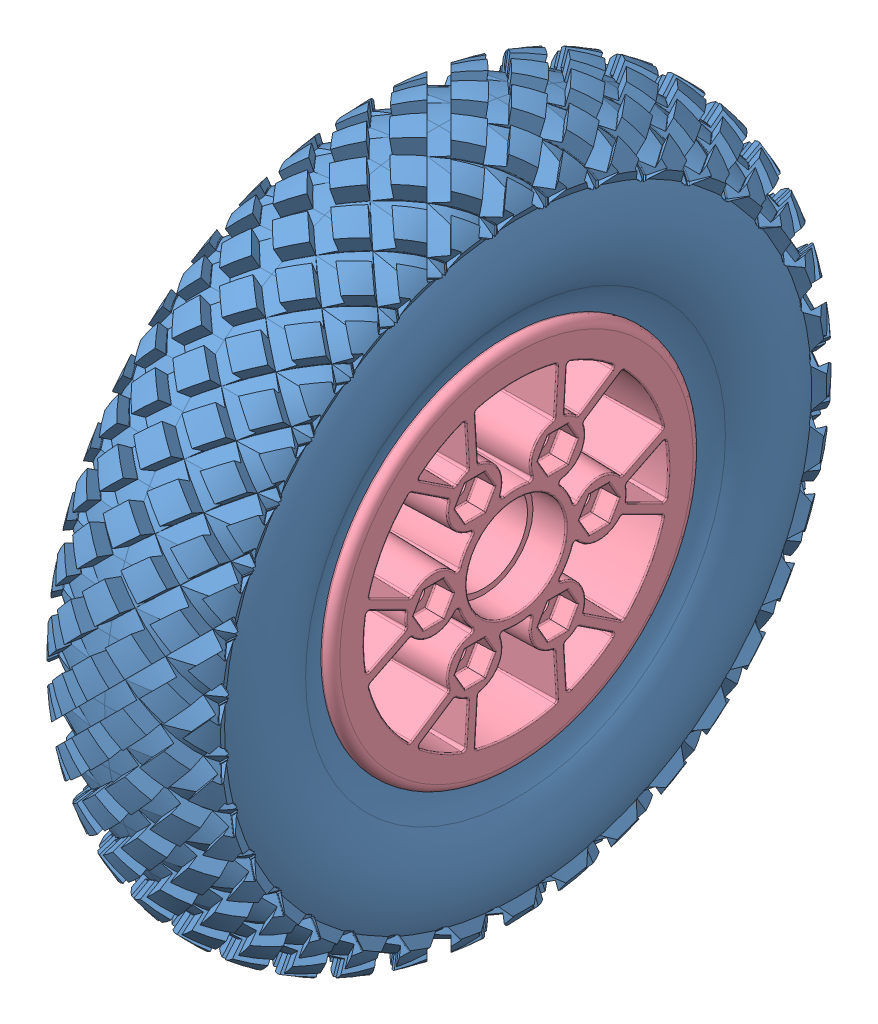
SolidWorks assembly 8Inch_Pneumatic_Wheel, configuration Default. Lengths in mm.
Overall size (54.46 203.4 203.4).
11 component instances, 4 part files, 0 mates.
Components (placement in the parent):
- Tire-1: Tire [Default] at (-14.0642 3.9407 4.9955) x (0 0 1) z (-1 0 0) size (203.4 203.4 50.81)
- Valve-1: Valve [Default] at (-14.5404 48.2951 4.9955) x (0 1 0) z (0 0 1) size (16.51 34.98 12.8)
- Pneumatic Hub-1: Pneumatic Hub [Default] at (-8.6594 5.0758 -4.0835) size (45.47 106.55 106.55)
  - #4x1.00, Plastic Thread Rolling Screw, Pan Head, Cross Recessed, Zinc Plated (Plastic Applications)_-1: #4x1.00, Plastic Thread Rolling Screw, Pan Head, Cross Recessed, Zinc Plated (Plastic Applications)_ [Default] at (7.3269 34.0601 29.3991) x (-1 0 0) z (0 -0.924225 -0.381849) size (27.43 5.56 5.56)
  - Hub-1: Hub [Default] at (-28.6141 -1.1351 9.0791) size (25.79 106.55 106.55)
  - #4x1.00, Plastic Thread Rolling Screw, Pan Head, Cross Recessed, Zinc Plated (Plastic Applications)_-2: #4x1.00, Plastic Thread Rolling Screw, Pan Head, Cross Recessed, Zinc Plated (Plastic Applications)_ [Default] at (7.3269 -1.1351 -31.5609) x (-1 0 0) z (0 0.131421 0.991327) size (27.43 5.56 5.56)
  - #4x1.00, Plastic Thread Rolling Screw, Pan Head, Cross Recessed, Zinc Plated (Plastic Applications)_-3: #4x1.00, Plastic Thread Rolling Screw, Pan Head, Cross Recessed, Zinc Plated (Plastic Applications)_ [Default] at (-19.0891 -1.1351 49.7191) x (1 0 0) z (0 -0.750107 0.661316) size (27.43 5.56 5.56)
  - #4x1.00, Plastic Thread Rolling Screw, Pan Head, Cross Recessed, Zinc Plated (Plastic Applications)_-4: #4x1.00, Plastic Thread Rolling Screw, Pan Head, Cross Recessed, Zinc Plated (Plastic Applications)_ [Default] at (7.3269 -36.3304 29.3991) x (-1 0 0) z (0 0.792804 -0.609477) size (27.43 5.56 5.56)
  - #4x1.00, Plastic Thread Rolling Screw, Pan Head, Cross Recessed, Zinc Plated (Plastic Applications)_-5: #4x1.00, Plastic Thread Rolling Screw, Pan Head, Cross Recessed, Zinc Plated (Plastic Applications)_ [Default] at (-19.0891 34.0601 -11.2409) x (1 0 0) z (0 0.94777 0.318954) size (27.43 5.56 5.56)
  - #4x1.00, Plastic Thread Rolling Screw, Pan Head, Cross Recessed, Zinc Plated (Plastic Applications)_-6: #4x1.00, Plastic Thread Rolling Screw, Pan Head, Cross Recessed, Zinc Plated (Plastic Applications)_ [Default] at (-19.0891 -36.3304 -11.2409) x (1 0 0) z (0 -0.197663 -0.98027) size (27.43 5.56 5.56)
  - Hub-2: Hub [Default] at (16.8519 -1.1351 9.0791) x (-1 0 0) z (0 0 -1) size (25.79 106.55 106.55)
